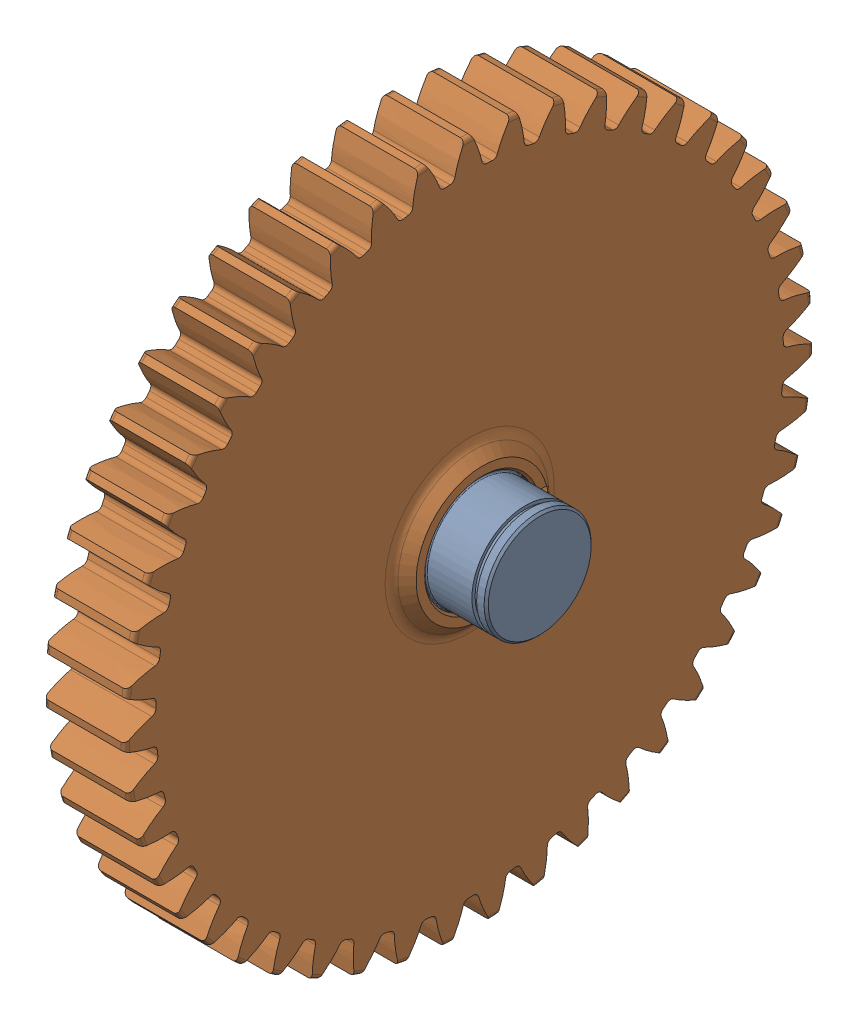
SolidWorks assembly g1_3_1_1_3_1, configuration 默认. Lengths in mm.
Overall size (103.5 321.87 322.01).
2 component instances, 2 part files, 0 mates.
Components (placement in the parent):
- g1_3_1_1_3-1_1-1: g1_3_1_1_3-1_1 [默认] at origin size (103.5 52 52)
- _X2_60F08F6E_X0_g1_3_1_1_3-2_1-1: _X2_60F08F6E_X0_g1_3_1_1_3-2_1 [默认] at (25 0 0) x (0 0 1) z (1 0 0) size (322.01 321.87 50.08)
